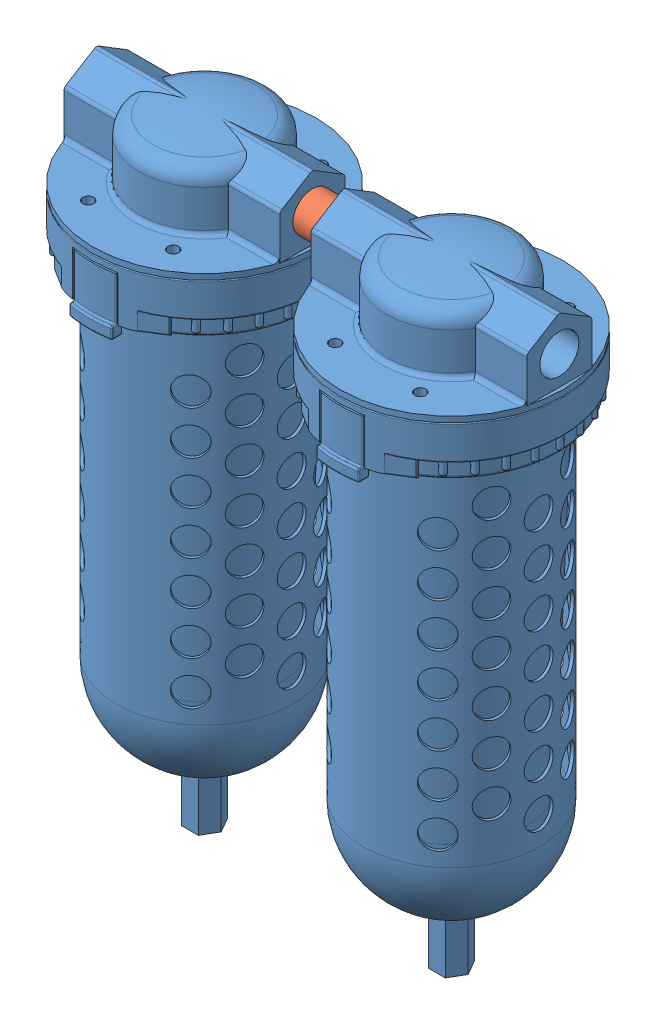
SolidWorks assembly ReadingTech_3P-060-P03-DC, configuration Default. Lengths in mm.
Overall size (206.63 271.66 99.95).
3 component instances, 2 part files, 3 mates.
Components (placement in the parent):
- ReadingTech_3P060P03F-1: ReadingTech_3P060P03F [Default] at (-16.0408 -88.9219 2.9722) size (98.17 271.66 99.95)
- ReadingTech_3P060P03F-2: ReadingTech_3P060P03F [Default] at (92.4172 -88.9219 2.9722) size (98.17 271.66 99.95)
- ReadingTech- 60cfm_connector_.375in-1: ReadingTech- 60cfm_connector_.375in [Default] at (45.0462 126.9781 2.9722) x (0 1 0) z (0 0 1) size (17.14 13.72 17.14)
Mates (geometry in assembly coordinates):
- Coincident1: coincident anti-aligned: circle of ReadingTech_3P060P03F-1; circle of ReadingTech- 60cfm_connector_.375in-1
- Coincident2: coincident aligned: circle of ReadingTech_3P060P03F-2; circle of ReadingTech- 60cfm_connector_.375in-1
- Coincident3: coincident aligned: plane of ReadingTech_3P060P03F-1 through (31.3302 114.2781 17.2597) normal (0 0 1); plane of ReadingTech_3P060P03F-2 through (139.7882 114.2781 17.2597) normal (0 0 1)
